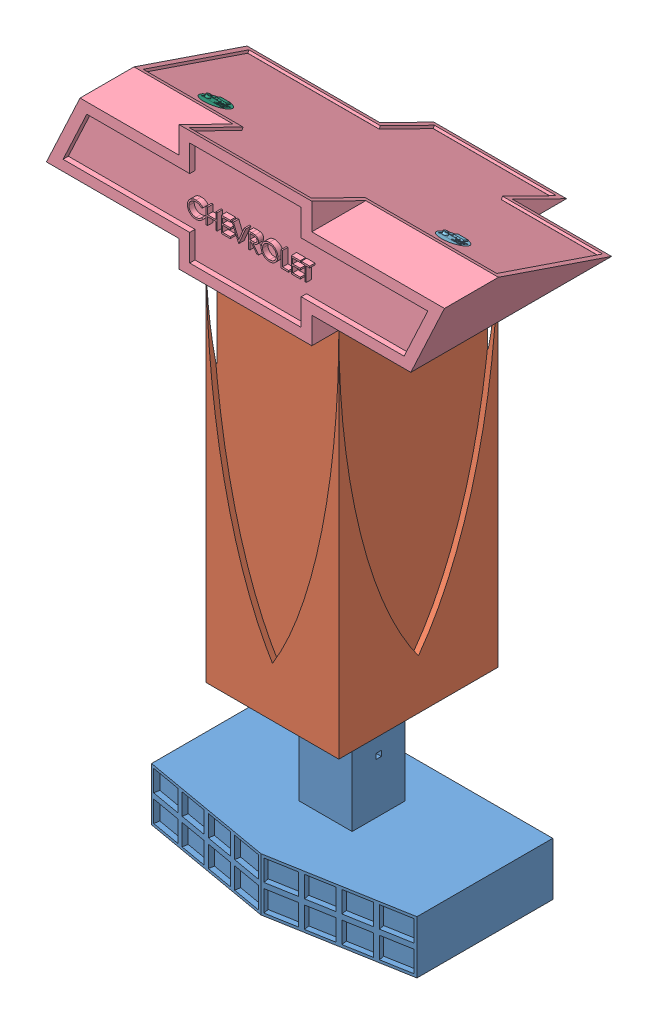
SolidWorks assembly Part B Assembly, configuration Default. Lengths in mm.
Overall size (750 1241.45 480).
6 component instances, 6 part files, 12 mates.
Components (placement in the parent):
- Base-1: Base [Default] at (136.291 -261.794 105.9401) size (500 600 300)
- Centre-1: Centre [Default] at (136.191 343.706 83.8992) size (276.64 700 326.64)
- pin-1: pin [Default] at (186.291 -11.794 233.8992) x (0 0 1) z (-1 0 0) size (11 11 100.2)
- Badge-1: Badge [Default] at (261.191 693.706 -45.1418) size (750 285.95 480)
- Mic USB-1: Mic USB [Default] at (399.1835 803.8247 303.5565) x (1 0 0) z (0 0.44114 0.897438) size (50 54 50)
- Mic USB 2-1: Mic USB 2 [Default] at (-48.0365 803.8247 303.5565) x (1 0 0) z (0 0.44114 0.897438) size (50 54 50)
Mates (geometry in assembly coordinates):
- Coincident1: coincident anti-aligned: plane of Base-1 through (386.291 -106.794 238.8992) normal (0 0 -1); plane of pin-1 through (86.291 -6.794 238.8992) normal (0 0 1)
- Coincident2: coincident anti-aligned: plane of Base-1 through (386.291 -6.794 238.8992) normal (0 0 -1); plane of pin-1 through (86.291 -6.794 238.8992) normal (0 0 1)
- Coincident3: coincident anti-aligned: plane of Base-1 through (386.291 -6.794 228.8992) normal (0 -1 0); plane of pin-1 through (86.291 -6.794 228.8992) normal (0 1 0)
- Coincident4: coincident aligned: line of Base-1 through (186.291 -6.794 228.8992) axis (0 -1 0); line of pin-1 through (186.291 -6.794 228.8992) axis (0 -1 0)
- Coincident5: coincident aligned: line of Centre-1 through (86.191 -6.294 283.8992) axis (0 0 -1); line of pin-1 through (86.191 -6.294 239.3992) axis (0 0 -1)
- Coincident6: coincident anti-aligned: plane of Base-1 through (86.291 288.206 183.8992) normal (0 0 -1); plane of Centre-1 through (86.191 493.706 183.8992) normal (0 0 1)
- Coincident7: coincident anti-aligned: plane of Centre-1 through (186.191 643.706 283.8992) normal (0 1 0); plane of Badge-1 through (136.191 643.706 -226.2398) normal (0 -1 0)
- Coincident8: coincident anti-aligned: plane of Centre-1 through (186.191 643.706 183.8992) normal (-1 0 0); plane of Badge-1 through (186.191 643.706 -226.2398) normal (1 0 0)
- Coincident9: coincident aligned: line of Centre-1 through (86.191 643.706 283.8992) axis (0 1 0); line of Badge-1 through (86.191 643.706 283.8992) axis (0 1 0)
- Concentric1: concentric aligned: cylinder of Badge-1 through (374.1835 803.8247 303.5565) axis (0 0.897438 -0.44114) radius 25; cylinder of Mic USB-1 through (374.1835 848.6966 281.4995) axis (0 0.897438 -0.44114) radius 25
- Coincident10: coincident aligned: circle of Badge-1; circle of Mic USB-1
- Coincident11: coincident aligned: circle of Badge-1; circle of Mic USB 2-1
